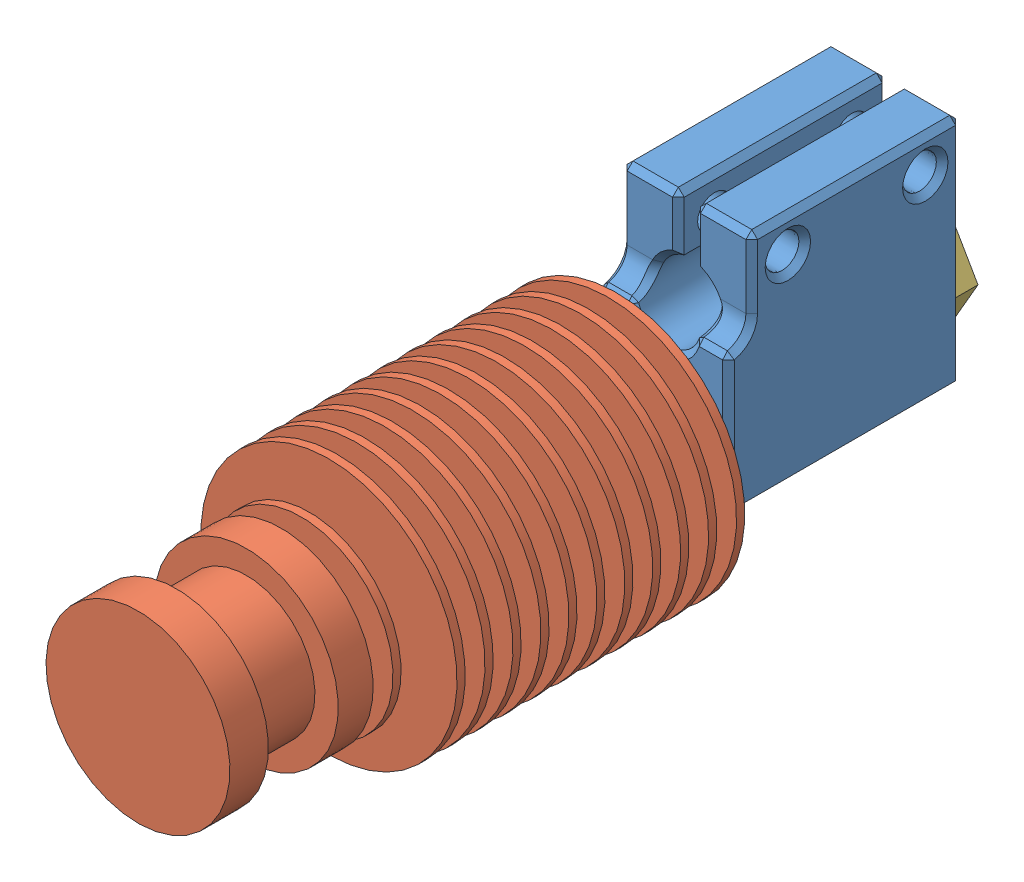
SolidWorks assembly Hotend Volcano J-head V6, configuration Valor predeterminado. Lengths in mm.
Overall size (26.65 28.32 70.3).
4 component instances, 4 part files, 15 mates.
Components (placement in the parent):
- Bloco Aquecedor-1: Bloco Aquecedor [Valor predeterminado] at origin size (11.2 20 20)
- Dissipador-1: Dissipador [Valor predeterminado] at (0.7469 3.7969 -4) x (0 0 -1) z (0.240623 -0.970619 0) size (41.1 22 22)
- Bico 0.4mm-1: Bico 0.4mm [Valor predeterminado] x (-1 0 0) z (0 0 -1) size (7.85 6.8 5.2)
- Tubo conector-1: Tubo conector [Valor predeterminado] at (0.7469 3.7969 24) x (-0.240623 0.970619 0) z (0 0 -1) size (6.8 6.8 4)
Mates (geometry in assembly coordinates):
- Coincidente1: coordinate: point of bloco aquecedor-1
- Concêntrico1: concentric aligned: cylinder of bloco aquecedor-1 through (5.6 5 20) axis (0 0 -1) radius 2.9; cylinder of Peça1^Hotend Volcano J-head V6-1 through (5.6 5 24) axis (0 0 -1) radius 11
- Distância1: distance = 4 mm anti-aligned: plane of bloco aquecedor-1 through (5.6 12.55 20) normal (0 0 1); plane of Peça1^Hotend Volcano J-head V6-1 through (5.6 5 24) normal (0 0 -1)
- No local2: in place: plane of Bloco Aquecedor-1 through (5.6 12.55 0) normal (0 0 -1); plane of Bico 0.4mm-1 through (0 0 0) normal (0 0 -1); moOrthogonalPlaneRef_w of Bloco Aquecedor-1 through (5.6 12.55 0) normal (0 0 -1); plane of Bico 0.4mm-1 through (0 0 0) normal (0 1 0); plane of Bloco Aquecedor-1 through (5.6 12.55 0) normal (0 0 -1); plane of Bico 0.4mm-1 through (0 0 0) normal (-1 0 0); plane of Bloco Aquecedor-1 through (5.6 12.55 0) normal (0 0 -1); unknown of Bico 0.4mm-1
- Coincidente5: coincident aligned: plane of ?; plane of ?
- Coincidente6: coincident aligned: moOrthogonalPlaneRef_w of bloco aquecedor-1 through (0 0 0) normal (0 1 0); plane of Peça2^Hotend Volcano J-head V6-1 through (0 0 0) normal (0 1 0)
- Coincidente7: coincident anti-aligned: moOrthogonalPlaneRef_w of bloco aquecedor-1 through (0 0 0) normal (1 0 0); plane of Peça2^Hotend Volcano J-head V6-1 through (0 0 0) normal (-1 0 0)
- No local3: in place: plane of Dissipador-1 through (5.6 5 24) normal (0 0 -1); plane of ? through (0 0 24) normal (0 0 -1); plane of Dissipador-1 through (5.6 5 24) normal (0 0 -1); plane of ? through (0 0 24) normal (0 1 0); plane of Dissipador-1 through (5.6 5 24) normal (0 0 -1); plane of ? through (0 0 24) normal (-1 0 0); plane of Dissipador-1 through (5.6 5 24) normal (0 0 -1); unknown of Tubo conector-1
- Coincidente8: coincident aligned: plane of ?; plane of ?
- Coincidente9: coincident aligned: moOrthogonalPlaneRef_w of Peça1^Hotend Volcano J-head V6-1 through (0.7469 3.7969 24) normal (0.970619 0.240623 0); plane of Peça3^Hotend Volcano J-head V6-1 through (0.7469 3.7969 24) normal (0.970619 0.240623 0)
- Coincidente10: coincident anti-aligned: moOrthogonalPlaneRef_w of Peça1^Hotend Volcano J-head V6-1 through (0.7469 3.7969 24) normal (0.240623 -0.970619 0); plane of Peça3^Hotend Volcano J-head V6-1 through (0.7469 3.7969 24) normal (-0.240623 0.970619 0)
- No local4: in place: plane of Dissipador-1 through (16.2768 7.6468 48.7) normal (0 0 1); plane of ? through (0 0 48.7) normal (0 0 1); plane of Dissipador-1 through (16.2768 7.6468 48.7) normal (0 0 1); plane of ? through (0 0 48.7) normal (0 1 0); plane of Dissipador-1 through (16.2768 7.6468 48.7) normal (0 0 1); plane of ? through (0 0 48.7) normal (1 0 0); plane of Dissipador-1 through (16.2768 7.6468 48.7) normal (0 0 1); unknown of ?
- Coincidente12: coincident aligned: plane of ?; plane of ?
- Coincidente13: coincident aligned: moOrthogonalPlaneRef_w of Dissipador-1 through (0.7469 3.7969 48.7) normal (0.970619 0.240623 0); plane of Acoplador da ventoinha-1 through (0.7469 3.7969 48.7) normal (0.970619 0.240623 0)
- Coincidente14: coincident anti-aligned: moOrthogonalPlaneRef_w of Dissipador-1 through (0.7469 3.7969 48.7) normal (-0.240623 0.970619 0); plane of Acoplador da ventoinha-1 through (0.7469 3.7969 48.7) normal (0.240623 -0.970619 0)
